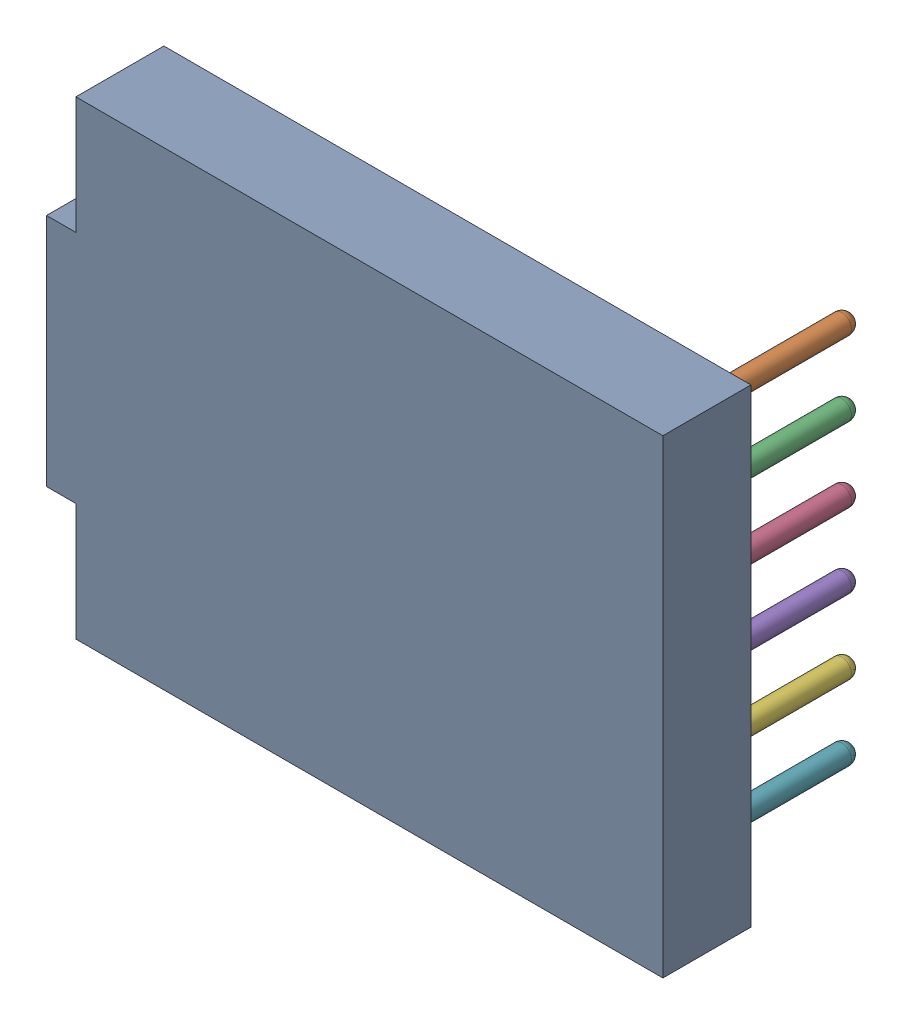
SolidWorks assembly Open CASCADE STEP translator 6.8 1.15.1, configuration Défaut. Lengths in mm.
Overall size (21 16 8.33).
7 component instances, 7 part files, 0 mates.
Components (placement in the parent):
- Body_1_8-1: Body_1_8 [Défaut] at origin size (21 16 3)
- Pin_1_5-1: Pin_1_5 [Défaut] x (0 -1 0) z (0 0 1) size (0.66 0.66 7.16)
- Pin_2_5-1: Pin_2_5 [Défaut] at (2.54 -2.54 0) x (0 -1 0) z (0 0 1) size (0.66 0.66 7.16)
- Pin_3_3-1: Pin_3_3 [Défaut] at (5.08 -5.08 0) x (0 -1 0) z (0 0 1) size (0.66 0.66 7.16)
- Pin_4_2-1: Pin_4_2 [Défaut] at (7.62 -7.62 0) x (0 -1 0) z (0 0 1) size (0.66 0.66 7.16)
- Pin_5_2-1: Pin_5_2 [Défaut] at (10.16 -10.16 0) x (0 -1 0) z (0 0 1) size (0.66 0.66 7.16)
- Pin_6_2-1: Pin_6_2 [Défaut] at (12.7 -12.7 0) x (0 -1 0) z (0 0 1) size (0.66 0.66 7.16)
